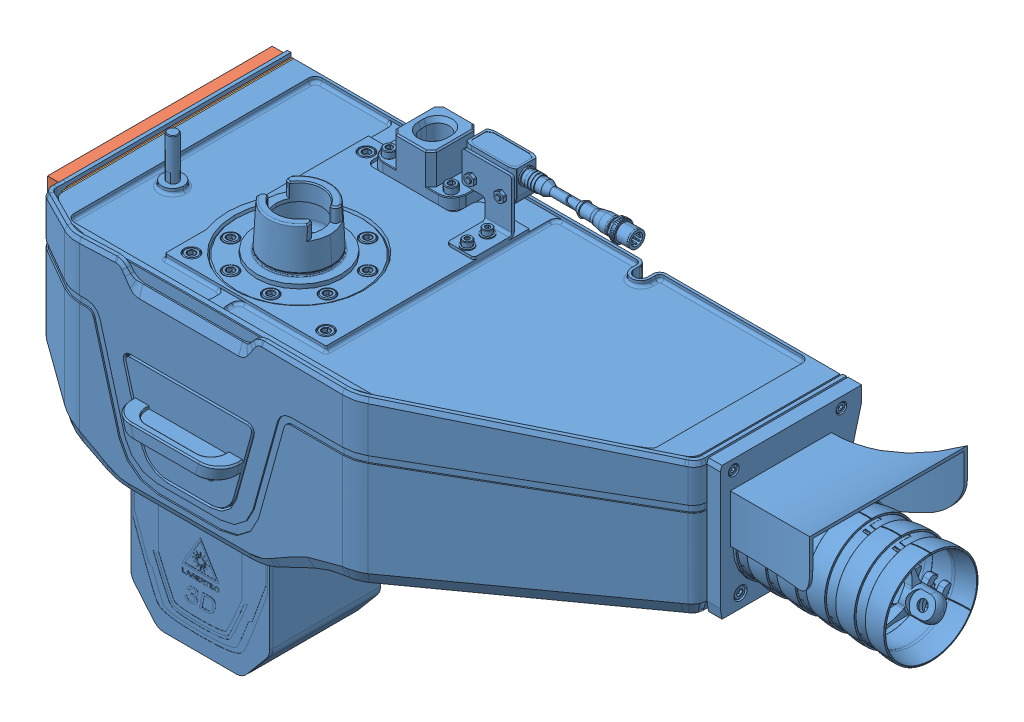
SolidWorks assembly Assemspacer, configuration Default. Lengths in mm.
Overall size (558.54 264.1 223.32).
3 component instances, 3 part files, 4 mates.
Components (placement in the parent):
- LASER_BASEHEAD_COAX9_SW2018-1: LASER_BASEHEAD_COAX9_SW2018 [Default] at origin size (548.59 264.1 223.32)
- LasertecMountingPlate_HOLEMOD-1: LasertecMountingPlate_HOLEMOD [Default] at (186.9473 174 -123.6003) x (0 0 1) z (-1 0 0) size (167 162.5 15)
- spacer-1: spacer [Default] at (187.9473 0 0) x (0 0 1) z (-1 0 0) size (171.68 10 1)
Mates (geometry in assembly coordinates):
- Coincident8: coincident anti-aligned: plane of LASER_BASEHEAD_COAX9_SW2018-1 through (186.9473 262.5 -156.1003) normal (-1 0 0); plane of LasertecMountingPlate_HOLEMOD-1 through (186.9473 174 -123.6003) normal (1 0 0)
- Coincident9: coincident: plane of LASER_BASEHEAD_COAX9_SW2018-1 through (187.9473 262.5 -223.1003) normal (-1 0 0); plane of spacer-1 through (187.9473 0 0) normal (1 0 0)
- Coincident10: coincident: line of LASER_BASEHEAD_COAX9_SW2018-1 through (187.9473 262.5 -223.1003) axis (0 1 0); line of spacer-1 through (187.9473 272.5 -223.1003) axis (0 -1 0)
- Coincident11: coincident anti-aligned: line of LASER_BASEHEAD_COAX9_SW2018-1 through (187.9473 272.5 -223.1003) axis (0 0 1); line of spacer-1 through (187.9473 272.5 -51.4191) axis (0 0 -1)
